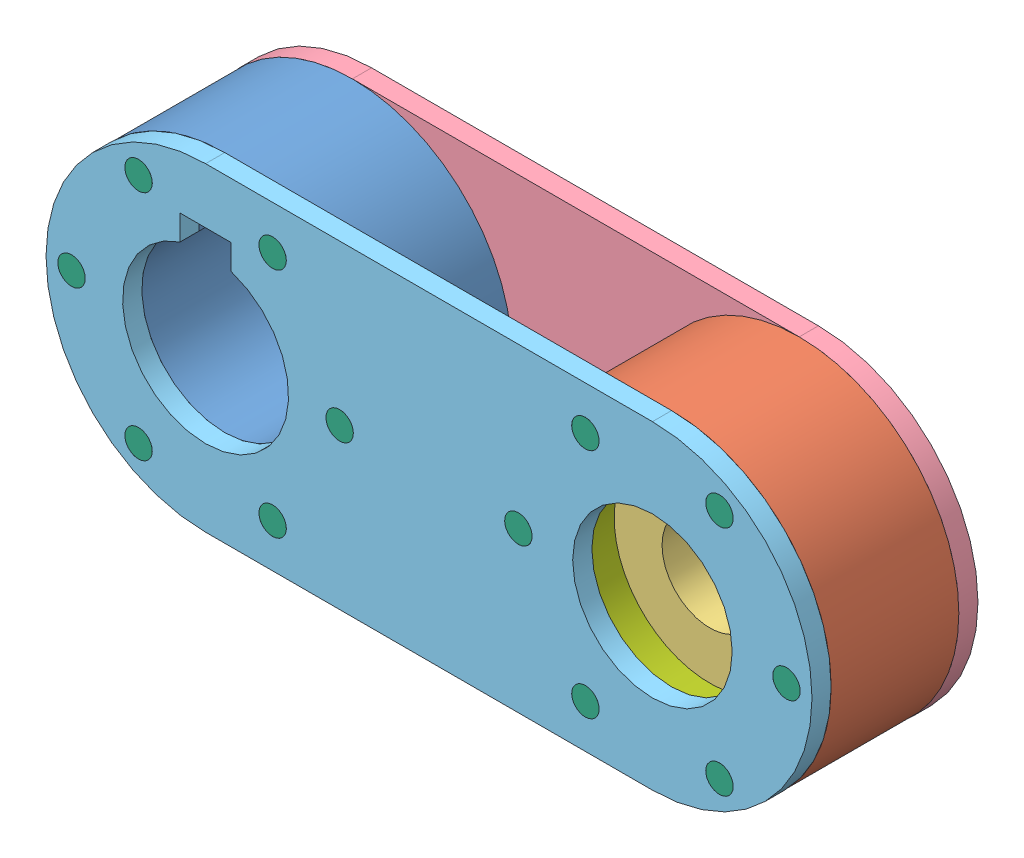
SolidWorks assembly manivela derecha, configuration Predeterminado. Lengths in mm.
Overall size (120 50 26).
18 component instances, 7 part files, 39 mates.
Components (placement in the parent):
- cople flecha-1: cople flecha [Predeterminado] at origin size (50 50 20)
- cople rodamiento-1: cople rodamiento [Predeterminado] at (70 0 0) size (50 50 20)
- rodameitno falso-1: rodameitno falso [Predeterminado] at (70 0 0) size (35 35 14)
- placa manivela 2-4: placa manivela 2 [Predeterminado] at (0 0 -3) size (120 50 3)
- placa manivela-3: placa manivela [Predeterminado] at (0 0 20) size (120 50 3)
- tornillo falso-2: tornillo falso [Predeterminado] at (-10.5 18.1865 23) x (-0.923728 -0.383049 0) z (0 0 -1) size (4.3 4.3 26)
- tornillo falso-3: tornillo falso [Predeterminado] at (-21 0 23) x (-0.923728 -0.383049 0) z (0 0 -1) size (4.3 4.3 26)
- tornillo falso-4: tornillo falso [Predeterminado] at (-10.5 -18.1865 23) x (-0.923728 -0.383049 0) z (0 0 -1) size (4.3 4.3 26)
- tornillo falso-5: tornillo falso [Predeterminado] at (10.5 -18.1865 23) x (-0.923728 -0.383049 0) z (0 0 -1) size (4.3 4.3 26)
- tornillo falso-6: tornillo falso [Predeterminado] at (21 0 23) x (-0.923728 -0.383049 0) z (0 0 -1) size (4.3 4.3 26)
- tornillo falso-7: tornillo falso [Predeterminado] at (10.5 18.1865 23) x (-0.923728 -0.383049 0) z (0 0 -1) size (4.3 4.3 26)
- tornillo falso-8: tornillo falso [Predeterminado] at (59.5 18.1865 23) x (-0.923728 -0.383049 0) z (0 0 -1) size (4.3 4.3 26)
- tornillo falso-9: tornillo falso [Predeterminado] at (49 0 23) x (-0.923728 -0.383049 0) z (0 0 -1) size (4.3 4.3 26)
- tornillo falso-10: tornillo falso [Predeterminado] at (80.5 18.1865 23) x (-0.923728 -0.383049 0) z (0 0 -1) size (4.3 4.3 26)
- tornillo falso-11: tornillo falso [Predeterminado] at (59.5 -18.1865 23) x (-0.923728 -0.383049 0) z (0 0 -1) size (4.3 4.3 26)
- tornillo falso-12: tornillo falso [Predeterminado] at (80.5 -18.1865 23) x (-0.923728 -0.383049 0) z (0 0 -1) size (4.3 4.3 26)
- tornillo falso-13: tornillo falso [Predeterminado] at (91 0 23) x (-0.923728 -0.383049 0) z (0 0 -1) size (4.3 4.3 26)
- anillo manivela-1: anillo manivela [Predeterminado] at (70 0 14) x (0.996967 0.077829 0) z (0 0 1) size (35 35 6)
Mates (geometry in assembly coordinates):
- Concéntrica1: concentric aligned: cylinder of cople rodamiento-1 through (70 0 20) axis (0 0 -1) radius 17.5; cylinder of rodameitno falso-1 through (70 0 14) axis (0 0 -1) radius 17.5
- Coincidente2: coincident anti-aligned: plane of cople flecha-1 through (0 0 0) normal (0 0 -1); plane of placa manivela 2-4 through (0 0 0) normal (0 0 1)
- Concéntrica2: concentric aligned: cylinder of cople flecha-1 through (10.5 18.1865 20) axis (0 0 1) radius 2.15; cylinder of placa manivela 2-4 through (10.5 18.1865 0) axis (0 0 1) radius 2.25
- Concéntrica3: concentric aligned: cylinder of cople flecha-1 through (-10.5 -18.1865 20) axis (0 0 1) radius 2.15; cylinder of placa manivela 2-4 through (-10.5 -18.1865 0) axis (0 0 1) radius 2.25
- Coincidente3: coincident anti-aligned: plane of cople rodamiento-1 through (70 0 0) normal (0 0 -1); plane of placa manivela 2-4 through (0 0 0) normal (0 0 1)
- Concéntrica4: concentric aligned: cylinder of cople rodamiento-1 through (80.5 18.1865 20) axis (0 0 1) radius 2.15; cylinder of placa manivela 2-4 through (80.5 18.1865 0) axis (0 0 1) radius 2.25
- Concéntrica5: concentric aligned: cylinder of cople rodamiento-1 through (59.5 -18.1865 20) axis (0 0 1) radius 2.15; cylinder of placa manivela 2-4 through (59.5 -18.1865 0) axis (0 0 1) radius 2.25
- Coincidente4: coincident anti-aligned: plane of cople flecha-1 through (0 0 20) normal (0 0 1); plane of placa manivela-3 through (0 0 20) normal (0 0 -1)
- Concéntrica6: concentric aligned: cylinder of cople flecha-1 through (-10.5 18.1865 20) axis (0 0 1) radius 2.15; cylinder of placa manivela-3 through (-10.5 18.1865 23) axis (0 0 1) radius 2.25
- Concéntrica7: concentric aligned: cylinder of cople flecha-1 through (10.5 -18.1865 20) axis (0 0 1) radius 2.15; cylinder of placa manivela-3 through (10.5 -18.1865 23) axis (0 0 1) radius 2.25
- Concéntrica8: concentric aligned: cylinder of cople rodamiento-1 through (59.5 18.1865 20) axis (0 0 1) radius 2.15; cylinder of placa manivela-3 through (59.5 18.1865 23) axis (0 0 1) radius 2.25
- Concéntrica9: concentric aligned: cylinder of cople rodamiento-1 through (80.5 -18.1865 20) axis (0 0 1) radius 2.15; cylinder of placa manivela-3 through (80.5 -18.1865 23) axis (0 0 1) radius 2.25
- Concéntrica101: concentric aligned: cylinder of placa manivela-3 through (-10.5 18.1865 23) axis (0 0 1) radius 2.25; cylinder of tornillo falso-2 through (-10.5 18.1865 -3) axis (0 0 1) radius 2.15
- Coincidente5: coincident aligned: plane of placa manivela-3 through (0 0 23) normal (0 0 1); plane of tornillo falso-2 through (-10.5 18.1865 23) normal (0 0 1)
- Concéntrica111: concentric aligned: cylinder of placa manivela-3 through (-21 0 23) axis (0 0 1) radius 2.25; cylinder of tornillo falso-3 through (-21 0 -3) axis (0 0 1) radius 2.15
- Coincidente6: coincident aligned: plane of placa manivela-3 through (0 0 23) normal (0 0 1); plane of tornillo falso-3 through (-21 0 23) normal (0 0 1)
- Concéntrica121: concentric aligned: cylinder of placa manivela-3 through (-10.5 -18.1865 23) axis (0 0 1) radius 2.25; cylinder of tornillo falso-4 through (-10.5 -18.1865 -3) axis (0 0 1) radius 2.15
- Coincidente7: coincident aligned: plane of placa manivela-3 through (0 0 23) normal (0 0 1); plane of tornillo falso-4 through (-10.5 -18.1865 23) normal (0 0 1)
- Concéntrica131: concentric aligned: cylinder of placa manivela-3 through (10.5 -18.1865 23) axis (0 0 1) radius 2.25; cylinder of tornillo falso-5 through (10.5 -18.1865 -3) axis (0 0 1) radius 2.15
- Coincidente8: coincident aligned: plane of placa manivela-3 through (0 0 23) normal (0 0 1); plane of tornillo falso-5 through (10.5 -18.1865 23) normal (0 0 1)
- Concéntrica141: concentric aligned: cylinder of placa manivela-3 through (21 0 23) axis (0 0 1) radius 2.25; cylinder of tornillo falso-6 through (21 0 -3) axis (0 0 1) radius 2.15
- Coincidente9: coincident aligned: plane of placa manivela-3 through (0 0 23) normal (0 0 1); plane of tornillo falso-6 through (21 0 23) normal (0 0 1)
- Concéntrica151: concentric aligned: cylinder of placa manivela-3 through (10.5 18.1865 23) axis (0 0 1) radius 2.25; cylinder of tornillo falso-7 through (10.5 18.1865 -3) axis (0 0 1) radius 2.15
- Coincidente10: coincident aligned: plane of placa manivela-3 through (0 0 23) normal (0 0 1); plane of tornillo falso-7 through (10.5 18.1865 23) normal (0 0 1)
- Concéntrica161: concentric aligned: cylinder of placa manivela-3 through (59.5 18.1865 23) axis (0 0 1) radius 2.25; cylinder of tornillo falso-8 through (59.5 18.1865 -3) axis (0 0 1) radius 2.15
- Concéntrica171: concentric aligned: cylinder of placa manivela-3 through (49 0 23) axis (0 0 1) radius 2.25; cylinder of tornillo falso-9 through (49 0 -3) axis (0 0 1) radius 2.15
- Concéntrica181: concentric aligned: cylinder of placa manivela-3 through (80.5 18.1865 23) axis (0 0 1) radius 2.25; cylinder of tornillo falso-10 through (80.5 18.1865 -3) axis (0 0 1) radius 2.15
- Concéntrica191: concentric aligned: cylinder of placa manivela-3 through (59.5 -18.1865 23) axis (0 0 1) radius 2.25; cylinder of tornillo falso-11 through (59.5 -18.1865 -3) axis (0 0 1) radius 2.15
- Concéntrica201: concentric aligned: cylinder of placa manivela-3 through (80.5 -18.1865 23) axis (0 0 1) radius 2.25; cylinder of tornillo falso-12 through (80.5 -18.1865 -3) axis (0 0 1) radius 2.15
- Concéntrica211: concentric aligned: cylinder of placa manivela-3 through (91 0 23) axis (0 0 1) radius 2.25; cylinder of tornillo falso-13 through (91 0 -3) axis (0 0 1) radius 2.15
- Coincidente11: coincident aligned: plane of placa manivela-3 through (0 0 23) normal (0 0 1); plane of tornillo falso-8 through (59.5 18.1865 23) normal (0 0 1)
- Coincidente12: coincident aligned: plane of placa manivela-3 through (0 0 23) normal (0 0 1); plane of tornillo falso-9 through (49 0 23) normal (0 0 1)
- Coincidente13: coincident aligned: plane of placa manivela-3 through (0 0 23) normal (0 0 1); plane of tornillo falso-10 through (80.5 18.1865 23) normal (0 0 1)
- Coincidente14: coincident aligned: plane of placa manivela-3 through (0 0 23) normal (0 0 1); plane of tornillo falso-13 through (91 0 23) normal (0 0 1)
- Coincidente15: coincident aligned: plane of placa manivela-3 through (0 0 23) normal (0 0 1); plane of tornillo falso-11 through (59.5 -18.1865 23) normal (0 0 1)
- Coincidente16: coincident aligned: plane of placa manivela-3 through (0 0 23) normal (0 0 1); plane of tornillo falso-12 through (80.5 -18.1865 23) normal (0 0 1)
- Coincidente17: coincident anti-aligned: plane of rodameitno falso-1 through (70 0 0) normal (0 0 -1); circle of placa manivela 2-4
- Concéntrica212: concentric aligned: cylinder of cople rodamiento-1 through (70 0 20) axis (0 0 -1) radius 17.5; cylinder of anillo manivela-1 through (70 0 20) axis (0 0 -1) radius 17.5
- Coincidente18: coincident anti-aligned: plane of rodameitno falso-1 through (70 0 14) normal (0 0 1); plane of anillo manivela-1 through (70 0 14) normal (0 0 -1)
